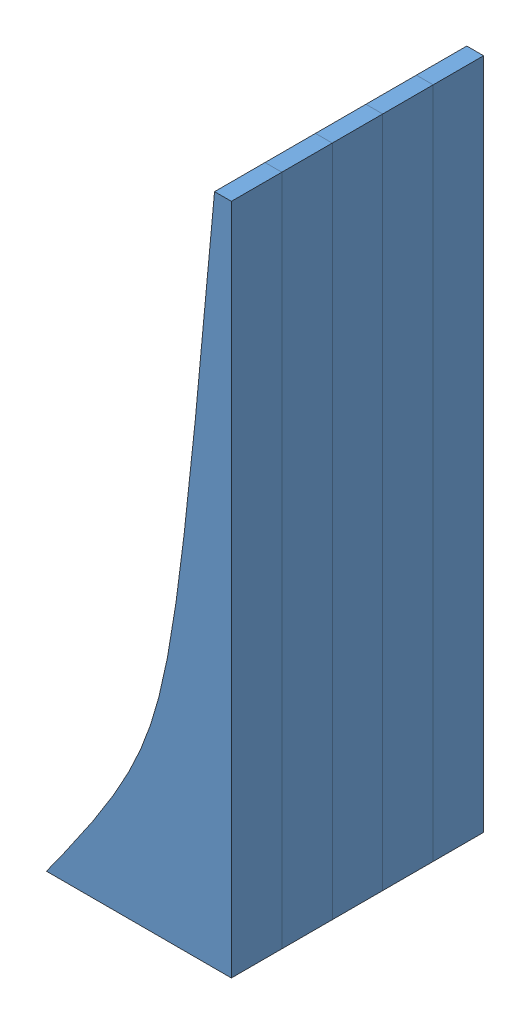
SolidWorks assembly Assem3, configuration Default. Lengths in mm.
Overall size (11 40 15).
5 component instances, 1 part files, 12 mates.
Components (placement in the parent):
- SlidePart1-1: SlidePart1 [Default] at (-31.5161 -16.4817 9.838) size (11 40 3)
- SlidePart1-2: SlidePart1 [Default] at (-31.5161 -16.4817 12.838) size (11 40 3)
- SlidePart1-3: SlidePart1 [Default] at (-31.5161 -16.4817 15.838) size (11 40 3)
- SlidePart1-4: SlidePart1 [Default] at (-31.5161 -16.4817 3.838) size (11 40 3)
- SlidePart1-5: SlidePart1 [Default] at (-31.5161 -16.4817 6.838) size (11 40 3)
Mates (geometry in assembly coordinates):
- Coincident1: coincident: plane of SlidePart1-1 through (-24.7612 -3.9094 12.838) normal (0 0 1); plane of SlidePart1-2 through (-24.7612 -3.9094 12.838) normal (0 0 -1)
- Coincident2: coincident: line of SlidePart1-1 through (-20.5161 -16.4817 12.838) axis (0 1 0); line of SlidePart1-2 through (-20.5161 -16.4817 12.838) axis (0 1 0)
- Coincident3: coincident aligned: line of SlidePart1-1 through (-20.5161 23.5183 12.838) axis (0 0 -1); line of SlidePart1-2 through (-20.5161 23.5183 15.838) axis (0 0 -1)
- Coincident4: coincident: plane of SlidePart1-2 through (-24.7612 -3.9094 15.838) normal (0 0 1); plane of SlidePart1-3 through (-24.7612 -3.9094 15.838) normal (0 0 -1)
- Coincident5: coincident: line of SlidePart1-2 through (-20.5161 -16.4817 15.838) axis (0 1 0); line of SlidePart1-3 through (-20.5161 -16.4817 15.838) axis (0 1 0)
- Coincident6: coincident aligned: line of SlidePart1-2 through (-20.5161 23.5183 15.838) axis (0 0 -1); line of SlidePart1-3 through (-20.5161 23.5183 18.838) axis (0 0 -1)
- Coincident7: coincident: plane of SlidePart1-1 through (-24.7612 -3.9094 9.838) normal (0 0 -1); plane of SlidePart1-5 through (-24.7612 -3.9094 9.838) normal (0 0 1)
- Coincident8: coincident: line of SlidePart1-1 through (-20.5161 -16.4817 9.838) axis (0 1 0); line of SlidePart1-5 through (-20.5161 -16.4817 9.838) axis (0 1 0)
- Coincident9: coincident: line of SlidePart1-1 through (-20.5161 23.5183 12.838) axis (0 0 -1); plane of SlidePart1-5 through (-21.5161 23.5183 9.838) normal (0 1 0)
- Coincident10: coincident: plane of SlidePart1-4 through (-24.7612 -12.298 6.838) normal (0 0 1); plane of SlidePart1-5 through (-24.7612 -3.9094 6.838) normal (0 0 -1)
- Coincident11: coincident: line of SlidePart1-4 through (-20.5161 -16.4817 6.838) axis (0 1 0); line of SlidePart1-5 through (-20.5161 -16.4817 6.838) axis (0 1 0)
- Coincident12: coincident aligned: line of SlidePart1-4 through (-20.5161 23.5183 6.838) axis (0 0 -1); line of SlidePart1-5 through (-20.5161 23.5183 9.838) axis (0 0 -1)
